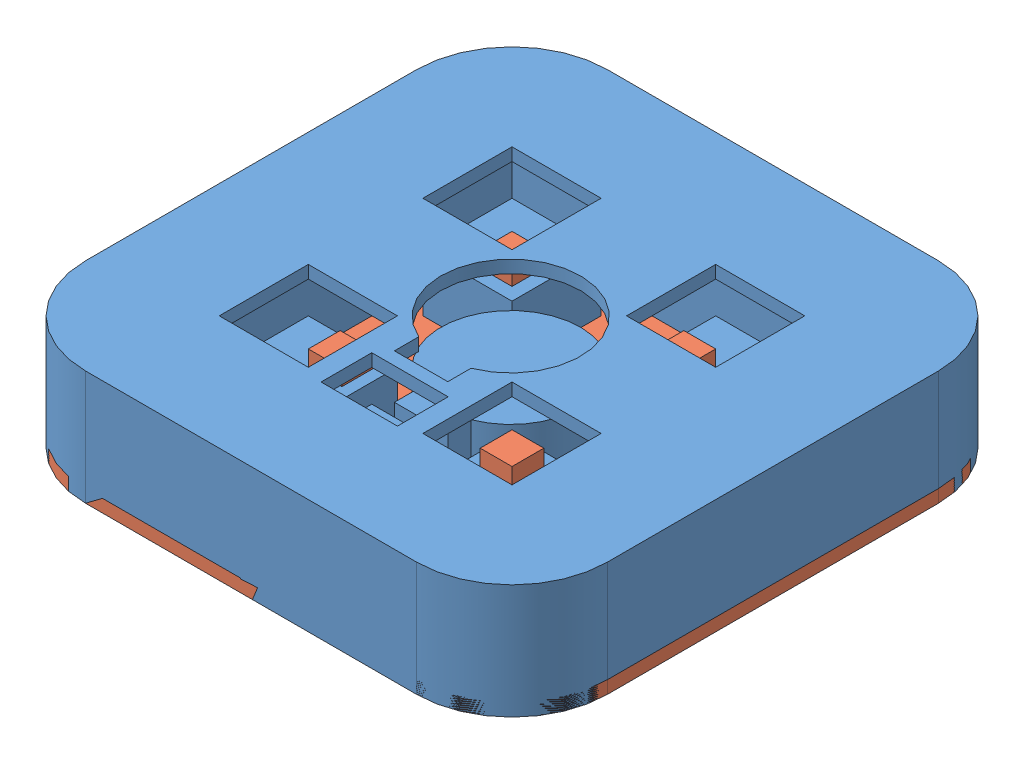
SolidWorks assembly assembly, configuration Default. Lengths in mm.
Overall size (82 19 82).
2 component instances, 2 part files, 1 mates.
Components (placement in the parent):
- kabilet_bunn-1: kabilet_bunn [Default] at (6.5479 40.4936 83.5885) size (82 19 82)
- kabilet_lokk-1: kabilet_lokk [Default] at (4.8512 41.4936 85.2301) size (82 13.5 82)
Mates (geometry in assembly coordinates):
- ProfileCenter1: profile center aligned: plane of kabilet_bunn-1 through (6.5479 41.4936 83.5885) normal (0 -1 0); plane of kabilet_lokk-1 through (7.6223 41.4936 30.459) normal (0 -1 0)
